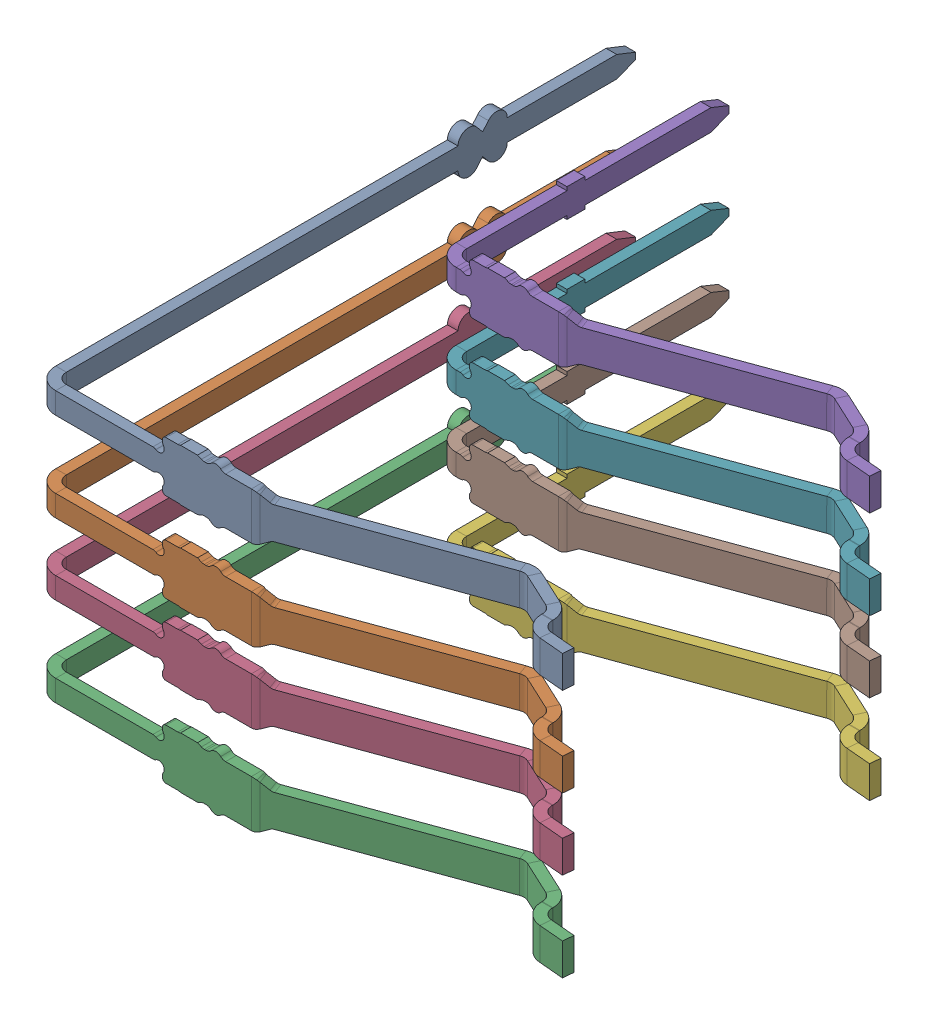
SolidWorks assembly leads_2.stp, configuration Default. Lengths in mm.
Overall size (14.29 8.54 16.6).
8 component instances, 2 part files, 0 mates.
Components (placement in the parent):
- top_lead.stp-1: top_lead.stp [Default] at origin size (14.29 1.54 16.6)
- top_lead.stp-2: top_lead.stp [Default] at (0 -2.5 0) size (14.29 1.54 16.6)
- top_lead.stp-3: top_lead.stp [Default] at (0 -7 0) size (14.29 1.54 16.6)
- top_lead.stp-4: top_lead.stp [Default] at (0 -4.5 0) size (14.29 1.54 16.6)
- bottom_lead.stp-1: bottom_lead.stp [Default] at origin size (11.67 1.54 7.97)
- bottom_lead.stp-2: bottom_lead.stp [Default] at (0 -7 0) size (11.67 1.54 7.97)
- bottom_lead.stp-3: bottom_lead.stp [Default] at (0 -2.5 0) size (11.67 1.54 7.97)
- bottom_lead.stp-4: bottom_lead.stp [Default] at (0 -4.5 0) size (11.67 1.54 7.97)
